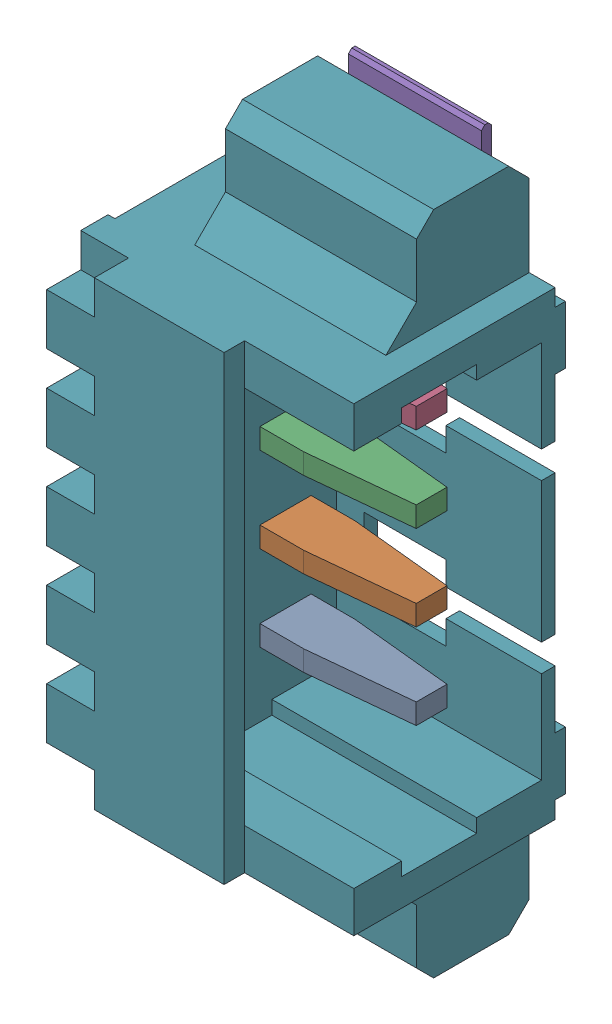
SolidWorks assembly J9, configuration Default. Lengths in mm.
Overall size (5.4 9.75 3.41).
8 component instances, 3 part files, 0 mates.
Components (placement in the parent):
- 653104131822-1: 653104131822 [Default] at (138.95 40.3999 1.69) x (0 1 0) z (0 0 1) size (9.75 5.4 3.41)
  - 6531xx131822_PIN_2-1: 6531xx131822_PIN_2 [Default] at (-1.875 2.7 -0.425) x (1 0 0) z (0 -1 0) size (0.3 1.48 4.54)
  - 6531xx131822_PIN_2-2: 6531xx131822_PIN_2 [Default] at (-0.625 2.7 -0.425) x (1 0 0) z (0 -1 0) size (0.3 1.48 4.54)
  - 6531xx131822_PIN_2-3: 6531xx131822_PIN_2 [Default] at (0.625 2.7 -0.425) x (1 0 0) z (0 -1 0) size (0.3 1.48 4.54)
  - 6531xx131822_PIN_2-4: 6531xx131822_PIN_2 [Default] at (1.875 2.7 -0.425) x (1 0 0) z (0 -1 0) size (0.3 1.48 4.54)
  - 6531xx131822_PIN_FLANGE_2-1: 6531xx131822_PIN_FLANGE_2 [Default] at (3.75 -0.045 -1.05) size (1.25 1.95 1.4)
  - 6531xx131822_PIN_FLANGE_2-2: 6531xx131822_PIN_FLANGE_2 [Default] at (-3.75 -0.045 -1.05) x (-1 0 0) z (0 0 1) size (1.25 1.95 1.4)
  - 653104131822-1: 653104131822 [Default] at origin size (9.75 4.2 3.4)
